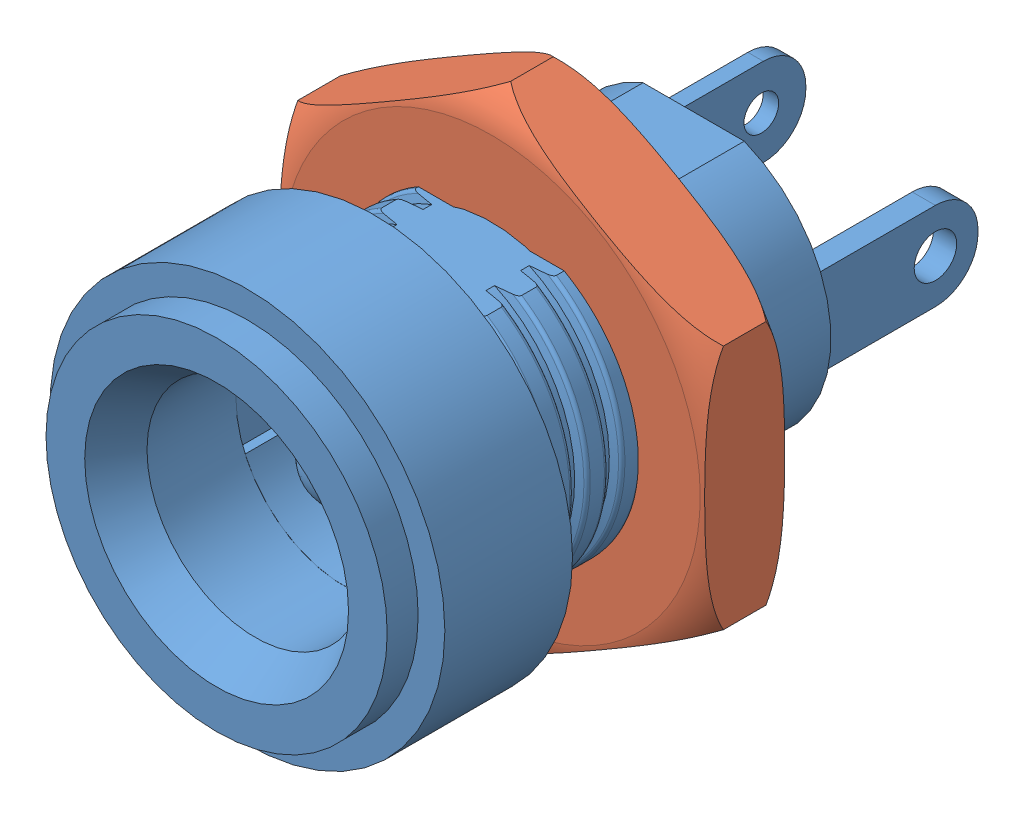
SolidWorks assembly DC Jack Panel Mount ASSY, configuration Default. Lengths in mm.
Overall size (17.52 16.47 17.63).
2 component instances, 2 part files, 3 mates.
Components (placement in the parent):
- DC Jack Panel Mount Base-1: DC Jack Panel Mount Base [Default] at origin size (10.2 10.2 17.63)
- DC Jack Panel Mount Nut-1: DC Jack Panel Mount Nut [Default] at (0 0 -7.35) x (0.866025 -0.5 0) z (0 0 1) size (13.88 11 3.18)
Mates (geometry in assembly coordinates):
- Concentric1: concentric: cylinder of DC Jack Panel Mount Base-1 through (0 0 0) axis (0 0 1) radius 5.1; cylinder of DC Jack Panel Mount Nut-1 through (0 -1.2484 0.997) axis (0 0 1) radius 3.4544
- Distance1: distance = 3 mm: plane of DC Jack Panel Mount Nut-1 through (0 0 -6.3) normal (0 0 1); plane of DC Jack Panel Mount Base-1 through (5.1 0 -3.3) normal (0 0 -1)
- Parallel1: parallel: plane of DC Jack Panel Mount Nut-1 through (5.5 -3.1754 -6.3) normal (1 0 0); plane of assembly through (0 0 0) normal (1 0 0)
